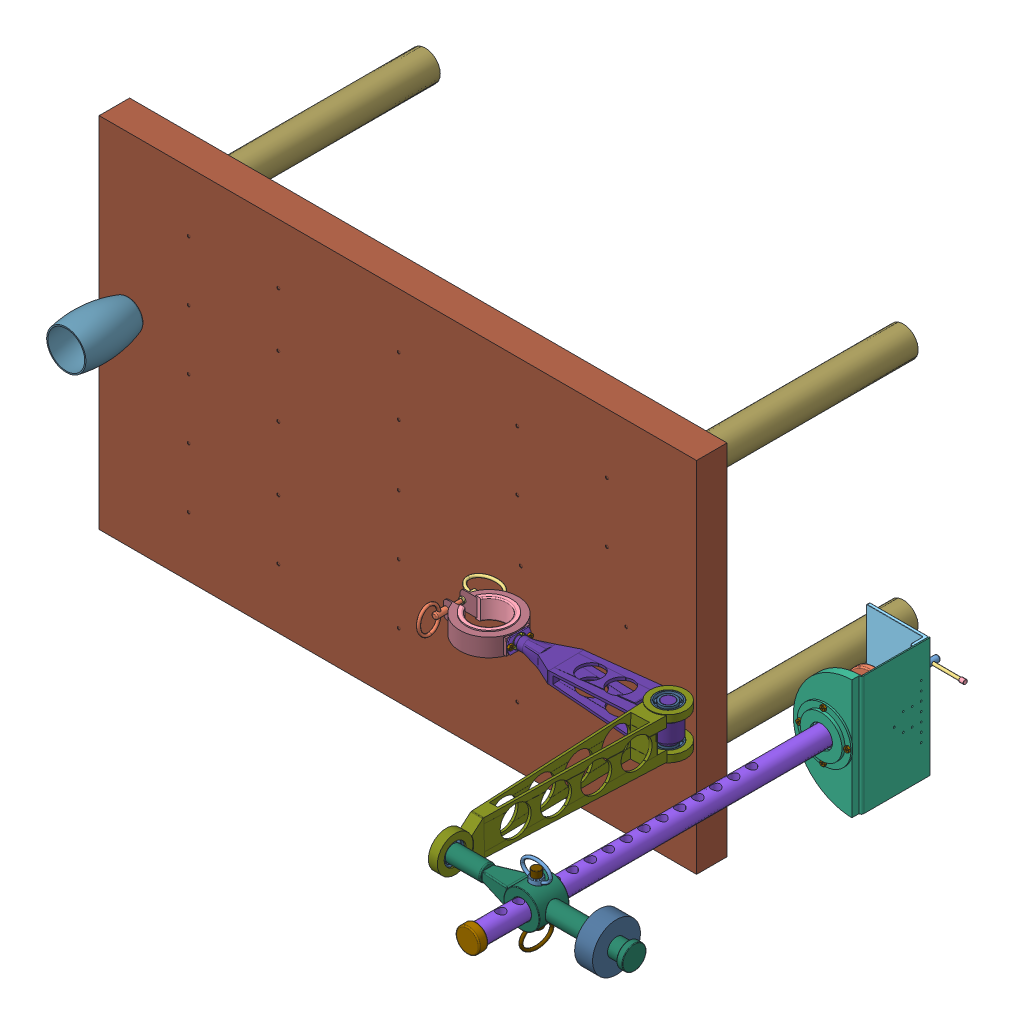
SolidWorks assembly сборка(30,05), configuration По умолчанию. Lengths in mm.
Overall size (1368.48 600 1034).
44 component instances, 28 part files, 0 mates.
Components (placement in the parent):
- Зажим1-1: Зажим1 [По умолчанию] at (-561.7181 632.2224 -489.8763) x (0.99999 -0.004361 0) z (0 0 1) size (10 10 110)
- Зажим2-1: Зажим2 [По умолчанию] at (-561.7181 632.2224 -374.8763) x (0.894231 0.447606 0) z (0 0 -1) size (80 80 15)
- Ручка1-1: Ручка1 [По умолчанию] at (-506.7186 631.9825 -477.8763) x (-0.003145 -0.721164 0.692758) z (-0.99999 0.004361 0) size (7 7 100)
- Ручка2-1: Ручка2 [По умолчанию] at (-503.7186 631.9694 -477.8763) x (-0.004344 -0.996188 -0.087124) z (-0.99999 0.004361 0) size (7 7 8)
- уголок-1: уголок [По умолчанию] at (-549.7181 632.2224 -412.8763) size (100 200 45)
- уголок2-1: уголок2 [По умолчанию] at (-497.7181 632.2224 -372.8763) x (0 0 1) z (-1 0 0) size (127 200 102)
- Стойка1-1: Стойка1 [По умолчанию] at (-545.243 632.2224 -299.8763) x (1 0 0) z (0 0 -1) size (90 90 9)
- Стержень1-1: Стержень1 [По умолчанию] at (-545.243 632.2224 -290.8763) x (0 1 0) z (0 0 1) size (35 35 614)
- Стержень1колпак-1: Стержень1колпак [По умолчанию] at (-545.243 632.2224 314.1237) x (-0.284183 -0.95877 0) z (0 0 -1) size (40 40 15)
- Шайба-вес-1: Шайба-вес [По умолчанию] at (-441.243 632.2224 198.6237) x (0 0.444959 -0.895551) z (1 0 0) size (80 80 30)
- Стол1-1: Стол1 [По умолчанию] at (-1249.7181 632.2224 -324.8763) size (1000 600 51)
- Стол-Ножка-1: Стол-Ножка [По умолчанию] at (-1649.7181 832.2224 -719.8763) x (0.51022 -0.860044 0) z (0 0 1) size (50 50 400)
- Стол-Ножка-2: Стол-Ножка [По умолчанию] at (-849.7181 432.2224 -719.8763) x (-0.098496 0.995137 0) z (0 0 1) size (50 50 400)
- Стол-Ножка-3: Стол-Ножка [По умолчанию] at (-849.7181 832.2224 -719.8763) x (-0.908934 0.416939 0) z (0 0 1) size (50 50 400)
- Стол-Ножка-4: Стол-Ножка [По умолчанию] at (-1649.7181 432.2224 -719.8763) x (0.814617 -0.579999 0) z (0 0 1) size (50 50 400)
- Вращение-обхват-1: Вращение-обхват [По умолчанию] at (-985.9576 618.1648 -162.6657) x (-0.003171 0.002728 -0.999991) z (0 0.999996 0.002728) size (97.5 109.9 30)
- Стакан-1: Стакан [По умолчанию] at (-1700.9508 668.9222 -274.8763) x (1 0 0) z (0 -1 0) size (72.92 104.75 74.31)
- Шайба-крепление1НОВ-1: Шайба-крепление1НОВ [По умолчанию] at (-545.243 632.2224 173.6237) x (-1 0 0) z (0 0 1) size (315 60.16 50)
- Стержень2НОВ-1: Стержень2НОВ [По умолчанию] at (-690.243 668.1761 -166.9296) x (1 0 0) z (0 -0.999997 -0.002609) size (60 425.65 70)
- Стержень4(НОВ)-1: Стержень4(НОВ) [По умолчанию] at (-689.6665 633.0849 -132.0258) x (0 -0.999997 -0.002609) z (-0.016472 0.002608 -0.999861) size (70 275.07 68)
- болт-1: болт [По умолчанию] at (-545.243 680.2224 198.6237) x (-0.008821 0 0.999961) z (0 -1 0) size (56.65 20 118.47)
- Болт-шайба-1: Болт-шайба [По умолчанию] at (-545.243 669.2224 198.6237) x (-0.999987 0 0.005011) z (0 -1 0) size (51.87 20 36.08)
- болт(мал)-1: болт(мал) [По умолчанию] at (-1042.4386 633.2325 -187.4457) x (-0.008672 -0.999959 -0.002701) z (0.003171 -0.002728 0.999991) size (49.05 10 89.62)
- Болт-шайба(мал))-1: Болт-шайба(мал)) [По умолчанию] at (-1042.4703 633.2598 -197.4457) x (0.999995 -0.000853 -0.003173) z (0.003171 -0.002728 0.999991) size (59.77 10 62.36)
- прокладка-1: прокладка [По умолчанию] at (-985.9576 618.1648 -162.6657) x (0.999995 0.000008 -0.003171) z (0 0.999996 0.002728) size (72.67 75 34.29)
- Bearing GB-T 292-2007 Type IN B7007 C-1: Bearing GB-T 292-2007 Type IN B7007 C [По умолчанию] at (-545.243 632.2224 -299.8763) x (0 0 1) z (-0.706224 -0.707988 0) size (14 62 62)
- крышка2-1: крышка2 [По умолчанию] at (-545.243 632.2224 -282.8763) x (0 -1 0) z (0 0 1) size (90 90 8)
- Bearing GB-T 292-2007 Type IN B7000 C-1: Bearing GB-T 292-2007 Type IN B7000 C [По умолчанию] at (-945.2078 633.1651 -162.754) x (0.999995 0.000008 -0.003171) z (-0.001784 0.828192 -0.560441) size (8 26 26)
- крышка3-1: крышка3 [По умолчанию] at (-935.2078 633.1652 -162.7857) x (0 0.999996 0.002728) z (-0.999995 -0.000008 0.003171) size (25.5 40 2)
- Bolt GB-T 29-2-1988 M5x10-1: Bolt GB-T 29-2-1988 M5x10 [По умолчанию] at (-935.1555 633.1202 -146.2859) x (-0.999995 -0.000008 0.003171) z (-0.002542 -0.595897 -0.803057) size (13.5 9.24 8)
- Bolt GB-T 29-2-1988 M5x10-2: Bolt GB-T 29-2-1988 M5x10 [По умолчанию] at (-935.2601 633.2102 -179.2856) x (-0.999995 -0.000008 0.003171) z (0.001172 0.928262 0.371925) size (13.5 9.24 8)
- Bolt GB-T 29-2-1988 M5x10-3: Bolt GB-T 29-2-1988 M5x10 [По умолчанию] at (-545.243 592.2224 -282.8763) x (0 0 -1) z (0.940322 -0.340286 0) size (13.5 9.24 8)
- Bolt GB-T 29-2-1988 M5x10-4: Bolt GB-T 29-2-1988 M5x10 [По умолчанию] at (-545.243 596.2224 -304.8763) x (0 0 1) z (0.166538 -0.986035 0) size (13.5 9.24 8)
- Bolt GB-T 29-2-1988 M5x10-5: Bolt GB-T 29-2-1988 M5x10 [По умолчанию] at (-514.0661 614.2224 -304.8763) x (0 0 1) z (0.888034 -0.459778 0) size (13.5 9.24 8)
- Bolt GB-T 29-2-1988 M5x10-6: Bolt GB-T 29-2-1988 M5x10 [По умолчанию] at (-576.4199 614.2224 -304.8763) x (0 0 1) z (0.845985 -0.533207 0) size (13.5 9.24 8)
- Bolt GB-T 29-2-1988 M5x10-7: Bolt GB-T 29-2-1988 M5x10 [По умолчанию] at (-514.0661 650.2224 -304.8763) x (0 0 1) z (-0.991097 0.133139 0) size (13.5 9.24 8)
- Bolt GB-T 29-2-1988 M5x10-8: Bolt GB-T 29-2-1988 M5x10 [По умолчанию] at (-545.243 672.2224 -282.8763) x (0 0 -1) z (0.336175 -0.941799 0) size (13.5 9.24 8)
- Bolt GB-T 29-2-1988 M5x10-9: Bolt GB-T 29-2-1988 M5x10 [По умолчанию] at (-505.243 632.2224 -282.8763) x (0 0 -1) z (0.420157 -0.907451 0) size (13.5 9.24 8)
- Bolt GB-T 29-2-1988 M5x10-10: Bolt GB-T 29-2-1988 M5x10 [По умолчанию] at (-576.4199 650.2224 -304.8763) x (0 0 1) z (0.716794 0.697285 0) size (13.5 9.24 8)
- Bolt GB-T 29-2-1988 M5x10-11: Bolt GB-T 29-2-1988 M5x10 [По умолчанию] at (-545.243 668.2224 -304.8763) x (0 0 1) z (0.937659 -0.347558 0) size (13.5 9.24 8)
- Bolt GB-T 29-2-1988 M5x10-12: Bolt GB-T 29-2-1988 M5x10 [По умолчанию] at (-585.243 632.2224 -282.8763) x (0 0 -1) z (0.836585 -0.547837 0) size (13.5 9.24 8)
- Bearing GB-T 292-2007 Type IN B7004 C-1: Bearing GB-T 292-2007 Type IN B7004 C [По умолчанию] at (-690.243 656.1761 -166.9609) x (0 0.999997 0.002609) z (-0.876769 -0.001255 0.48091) size (12 42 42)
- Bearing GB-T 292-2007 Type IN B7004 C-2: Bearing GB-T 292-2007 Type IN B7004 C [По умолчанию] at (-690.243 598.1763 -167.1122) x (0 0.999997 0.002609) z (0.5399 0.002196 -0.841726) size (12 42 42)
- Bearing GB-T 292-2007 Type IN B7004 C-3: Bearing GB-T 292-2007 Type IN B7004 C [По умолчанию] at (-696.243 632.2224 198.6237) x (1 0 0) z (0 -0.748463 -0.663177) size (12 42 42)
